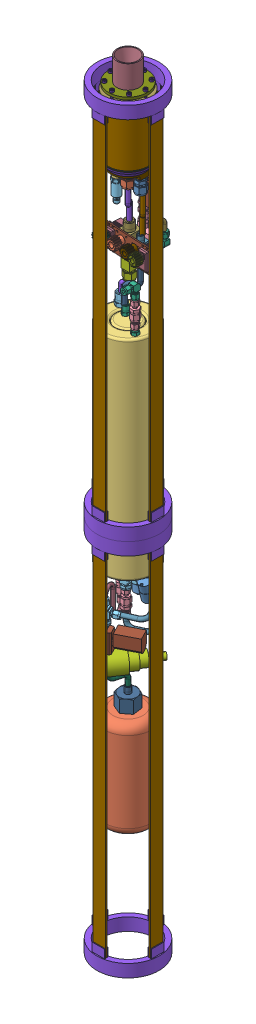
SolidWorks assembly Assemblage global, configuration Défaut. Lengths in mm.
Overall size (164.33 1851.66 164.33).
104 component instances, 54 part files, 42 mates.
Components (placement in the parent):
- AG2029-1: AG2029 [Défaut] at (-44.0948 -515.2209 332.3852) x (-0.187296 0.291343 -0.938104) z (-0.980646 0 0.195789) size (26.06 49.78 26.06)
- COPV-1: COPV [Défaut] at (-69.8493 -763.6515 345.7941) x (0.999999 0 -0.001097) z (0.001097 0 0.999999) size (111 247.05 111)
- reservoirs-1: reservoirs [Défaut] at (-63.3285 -459.1722 334.7401) x (0.861308 0 0.508083) z (0.508083 0 -0.861308) size (120 500 120)
- AG2029-2: AG2029 [Défaut] at (-74.1621 -512.8541 313.037) x (0.275712 0.022106 0.960986) z (0.961221 0 -0.275779) size (26.06 49.78 26.06)
- SS-CHS4-25-SwagelokCompany-3D-11-18-2022.stp-1: SS-CHS4-25-SwagelokCompany-3D-11-18-2022.stp [Défaut] at (-30.7659 29.6257 368.0986) x (0 1 0) z (-0.999992 0 0.003885) size (61.72 17.46 20.16)
- SS-CHS4-25-SwagelokCompany-3D-11-18-2022.stp-2: SS-CHS4-25-SwagelokCompany-3D-11-18-2022.stp [Défaut] at (-82.6779 -542.8366 338.0207) x (0 -1 0) z (0.566065 0 -0.82436) size (61.72 17.46 20.16)
- SS-CHS4-25-SwagelokCompany-3D-11-18-2022.stp-3: SS-CHS4-25-SwagelokCompany-3D-11-18-2022.stp [Défaut] at (-108.7134 -594.8623 323.1098) x (0 1 0) z (0.291825 0 -0.956472) size (61.72 17.46 20.16)
- SS-400-3-4TRT-SwagelokCompany-3D-11-18-2022.stp-2: SS-400-3-4TRT-SwagelokCompany-3D-11-18-2022.stp [Défaut] at (-88.4188 -547.9417 382.1181) x (0 -1 0) z (-0.911781 0 0.410677) size (61.21 20.32 39.95)
- SS-400-9-SwagelokCompany-3D-11-19-2022.stp-1: SS-400-9-SwagelokCompany-3D-11-19-2022.stp [Défaut] at (-32.0926 118.2717 394.9899) x (0.049277 0 -0.998785) z (0 1 0) size (35.14 14.22 35.14)
- SS-400-9-SwagelokCompany-3D-11-19-2022.stp-2: SS-400-9-SwagelokCompany-3D-11-19-2022.stp [Défaut] at (-85.1456 148.5076 291.806) x (-0.008726 -0.999962 0.000076) z (-0.008727 0 -0.999962) size (35.14 14.22 35.14)
- Détendeur Azote-1: Détendeur Azote [Défaut] at (-90.7987 -675.9247 398.6803) x (-0.827016 0 -0.562179) z (0.562179 0 -0.827016) size (50 50 118.8)
- structure_external-1: structure_external [Défaut] at (-54.807 -353.8101 198.1941) size (193.05 900.54 193.05)
  - ring-2: ring [Défaut] at (-15.0423 -34.6578 147.6) size (147.6 50 147.6)
  - rods_carbon-1: rods_carbon [Défaut] at (1414.5089 -1641.7579 78.8136) size (30 840 4)
  - rods_carbon-2: rods_carbon [Défaut] at (1414.5089 -1641.7579 212.3864) size (30 840 4)
  - rods_carbon-3: rods_carbon [Défaut] at (-83.8287 -1641.7579 -1281.9512) x (0 0 -1) z (1 0 0) size (30 840 4)
  - rods_carbon-4: rods_carbon [Défaut] at (53.7441 -1641.7579 1577.1512) x (0 0 1) z (-1 0 0) size (30 840 4)
  - ring-3: ring [Défaut] at (-15.0423 865.3422 147.6) x (-1 0 0) z (0 0 1) size (147.6 50 147.6)
  - case_rocket-1: case_rocket [Défaut] at (-15.0423 -35.1987 147.6) x (-0.316422 0 -0.948619) z (0.948619 0 -0.316422) size (152.6 900 152.6) (hidden)
- structure_external-2: structure_external [Défaut] at (-54.807 -1253.8101 198.1941) size (193.05 900.54 193.05)
  - ring-2: ring [Défaut] at (-15.0423 -34.6578 147.6) size (147.6 50 147.6)
  - rods_carbon-1: rods_carbon [Défaut] at (1414.5089 -1641.7579 78.8136) size (30 840 4)
  - rods_carbon-2: rods_carbon [Défaut] at (1414.5089 -1641.7579 212.3864) size (30 840 4)
  - rods_carbon-3: rods_carbon [Défaut] at (-83.8287 -1641.7579 -1281.9512) x (0 0 -1) z (1 0 0) size (30 840 4)
  - rods_carbon-4: rods_carbon [Défaut] at (53.7441 -1641.7579 1577.1512) x (0 0 1) z (-1 0 0) size (30 840 4)
  - ring-3: ring [Défaut] at (-15.0423 865.3422 147.6) x (-1 0 0) z (0 0 1) size (147.6 50 147.6)
  - case_rocket-1: case_rocket [Défaut] at (-15.0423 -35.1987 147.6) x (-0.316422 0 -0.948619) z (0.948619 0 -0.316422) size (152.6 900 152.6) (hidden)
- SS-16-RA-4-SwagelokCompany-3D-11-19-2022.stp-1: SS-16-RA-4-SwagelokCompany-3D-11-19-2022.stp [Défaut] at (-69.8493 -735.9786 345.7941) x (0 -1 0) z (0.129036 0 0.99164) size (49.78 41.27 47.66)
- SS-400-3-4TRT-SwagelokCompany-3D-11-18-2022.stp-6: SS-400-3-4TRT-SwagelokCompany-3D-11-18-2022.stp [Défaut] at (-82.6779 -492.923 338.0207) x (0 -1 0) z (-0.980646 0 0.195789) size (61.21 20.32 39.95)
- SS-400-3-4TRT-SwagelokCompany-3D-11-18-2022.stp-7: SS-400-3-4TRT-SwagelokCompany-3D-11-18-2022.stp [Défaut] at (-108.7134 -548.758 323.1098) x (0 1 0) z (-0.961221 0 0.275779) size (61.21 20.32 39.95)
- assemblage vanne-1: assemblage vanne [Défaut] at (-83.1452 273.6545 341.8828) x (0.998449 0 0.055666) z (0 -1 0) size (115.02 63.08 70.73)
  - support vanne servo-1: support vanne servo [Défaut] at (11.6117 -0.2898 118.0217) size (110 3 54)
  - SS-8P6T2-SwagelokCompany-3D-11-16-2022-1: SS-8P6T2-SwagelokCompany-3D-11-16-2022 [Défaut] at (-2.7383 -31.2778 99.9999) x (0 0 1) z (0 1 0) size (67.06 28.45 46.75)
  - Savox_SB2290SG Servo.stp-1: Savox_SB2290SG Servo.stp [Défaut] at (-30.1883 -2.5398 110) x (0 0 1) z (0 1 0) size (54 20.2 42.6)
  - SS-4P4T2-SwagelokCompany-3D-11-16-2022-1: SS-4P4T2-SwagelokCompany-3D-11-16-2022 [Défaut] at (30.8117 -21.3718 99.9999) x (0 0 1) z (0 1 0) size (48.26 18.8 31.12)
  - Savox_SB2290SG Servo.stp-3: Savox_SB2290SG Servo.stp [Défaut] at (55.6117 -2.5398 110.2) x (0 0 1) z (0 1 0) size (54 20.2 42.6)
  - GEAB1.5-20-15-B-10 v1.step-1: GEAB1.5-20-15-B-10 v1.step [Défaut] at (-30.1884 31.7992 99.9999) x (1 0 0) z (0 -1 0) size (33 33 15.01)
    - GEAB1.5-20-15-B-10_b.step-1: GEAB1.5-20-15-B-10_b.step [Défaut] at origin size (33 33 15.01)
  - GEAB1.5-15-15-B-10 v0.step-1: GEAB1.5-15-15-B-10 v0.step [Défaut] at (55.6116 16.3713 100.1999) x (1 0 0) z (0 1 0) size (25.44 25.39 15.01)
    - GEAB1.5-15-15-B-10_b.step-1: GEAB1.5-15-15-B-10_b.step [Défaut] at origin size (25.44 25.39 15.01)
  - GEAB1.5-15-15-B-10.stp-1: GEAB1.5-15-15-B-10.stp [Défaut] at (30.8117 27.2102 99.9999) x (0.94768 0 0.319221) z (0 -1 0) size (25.44 25.39 24.01)
    - SET-SCREW4-4.stp-1: SET-SCREW4-4.stp [Défaut] at (0 5 20) x (0 -1 0) z (-1 0 0) size (4 4 4)
    - GEAB1.5-15-15-B-10_b.stp-1: GEAB1.5-15-15-B-10_b.stp [Défaut] at origin size (25.44 25.39 24.01)
  - GEAB1.5-15-15-B-12.stp-1: GEAB1.5-15-15-B-12.stp [Défaut] at (-2.7383 27.2102 99.9999) x (0.774557 0 -0.632504) z (0 -1 0) size (25.44 25.39 24.01)
    - SET-SCREW4-3.stp-1: SET-SCREW4-3.stp [Défaut] at (0 6 20) x (0 -1 0) z (-1 0 0) size (3 4 4)
    - GEAB1.5-15-15-B-12_b.stp-1: GEAB1.5-15-15-B-12_b.stp [Défaut] at origin size (25.44 25.39 24.01)
  - raccord servo v2.step-1: raccord servo v2.step [Défaut] at (65.6117 16.7992 100.1999) x (1 0 0) z (0 -1 0) size (21 21 7)
  - raccord servo v2.step-2: raccord servo v2.step [Défaut] at (-20.1883 16.7992 99.9999) x (1 0 0) z (0 -1 0) size (21 21 7)
- SS-4R3A1-SwagelokCompany-3D-11-18-2022.stp-3: SS-4R3A1-SwagelokCompany-3D-11-18-2022.stp [Défaut] at (-84.9722 168.38 291.8045) x (0.99796 -0.008704 0.063248) z (0.008726 0.999962 -0.000076) size (51.64 20.24 98.81)
- SS-8-HN-RT-SwagelokCompany-3D-11-19-2022.stp-1: SS-8-HN-RT-SwagelokCompany-3D-11-19-2022.stp [Défaut] at (-108.7134 46.1814 323.1098) x (0 -1 0) z (0 0 1) size (46.74 22.23 25.66)
- SS-4-HN-RT-SwagelokCompany-3D-11-19-2022.stp-1: SS-4-HN-RT-SwagelokCompany-3D-11-19-2022.stp [Défaut] at (-82.8771 39.8314 338.3593) x (0 -1 0) z (0 0 1) size (35.56 14.29 16.5)
- SS-4-HN-RT-SwagelokCompany-3D-11-19-2022.stp-2: SS-4-HN-RT-SwagelokCompany-3D-11-19-2022.stp [Défaut] at (-82.6779 -467.2806 338.0207) x (0 -1 0) z (0 0 1) size (35.56 14.29 16.5)
- SS-4-HN-RT-SwagelokCompany-3D-11-19-2022.stp-3: SS-4-HN-RT-SwagelokCompany-3D-11-19-2022.stp [Défaut] at (-108.7134 -502.8406 323.1098) x (0 1 0) z (0 0 1) size (35.56 14.29 16.5)
- SS-4-HN-RT-SwagelokCompany-3D-11-19-2022.stp-5: SS-4-HN-RT-SwagelokCompany-3D-11-19-2022.stp [Défaut] at (-30.7659 39.8314 368.0986) x (0 -1 0) z (0 0 1) size (35.56 14.29 16.5)
- HC-810-3-SwagelokCompany-3D-11-19-2022.stp-1: HC-810-3-SwagelokCompany-3D-11-19-2022.stp [Défaut] at (-85.0713 157.6526 327.2391) x (0 -1 0) z (0.008727 0 0.999962) size (72.14 22.35 48.97)
- SS-400-9-SwagelokCompany-3D-11-19-2022.stp-5: SS-400-9-SwagelokCompany-3D-11-19-2022.stp [Défaut] at (-33.1986 194.8524 295.3224) x (-0.008131 -0.999924 -0.009303) z (0.99796 -0.008704 0.063248) size (35.14 14.22 35.14)
- tuyau_N20_bas_flex-1: tuyau_N20_bas_flex [Défaut] at (-67.8323 77.8106 330.25) x (0.985088 0 0.172054) z (-0.172054 0 0.985088) size (34 88 10)
- tuyau_N20_bas_flex-2: tuyau_N20_bas_flex [Défaut] at (-58.7499 259.7861 359.3238) x (0.634251 0 0.773127) z (-0.773127 0 0.634251) size (34 88 10)
- tuyau_eth_bas_flex-1: tuyau_eth_bas_flex [Défaut] at (-34.8493 240.253 345.7557) x (-0.688374 0 0.725356) z (-0.725356 0 -0.688374) size (10 102 32)
- tuyau_eth_haut_flex-1: tuyau_eth_haut_flex [Défaut] at (-18.4859 39.9352 328.5231) x (0.987138 0 -0.159869) z (0.159869 0 0.987138) size (43 115 10)
- soleno_quart-1: soleno_quart [Défaut] at (-61.5456 -650.9097 463.0875) x (0.457833 0 0.889038) z (0 1 0) size (28 80.02 47.02)
- soleno_quart-2: soleno_quart [Défaut] at (-20.3836 252.3792 237.2813) x (0.045071 0.008928 -0.998944) z (0.008131 0.999924 0.009303) size (28 80.02 47.02)
- tuyaux_vent_N20-1: tuyaux_vent_N20 [Défaut] at (-41.0336 189.9751 313.6956) x (-0.92086 0.011114 -0.389735) z (0.389808 0.005398 -0.92088) size (8 66 28)
- raccord1_pressure-1: raccord1_pressure [Défaut] at (-92.0789 -568.6899 372.0521) x (0.3218 0 0.946808) z (-0.946808 0 0.3218) size (70 88 8)
- raccord2_pressure-1: raccord2_pressure [Défaut] at (-56.8793 -576.2937 327.536) x (-0.410675 -0.003257 -0.911776) z (-0.001338 0.999995 -0.00297) size (46.01 60.01 60.01)
- raccord3_pressure-1: raccord3_pressure [Défaut] at (-73.9394 -725.8218 361.2221) x (0.256259 0 -0.966608) z (0.966608 0 0.256259) size (47.59 69.3 10)
- Demo A2 98mm V02-1: Demo A2 98mm V02 [Standard] at (-69.8493 355.3689 345.7941) x (0.998956 0 -0.04569) z (-0.04569 0 -0.998956) size (138.59 315.92 138.59)
  - Injector 98mm V02-1: Injector 98mm V02 [Standard] at (0 -14 0) size (138.59 129.3 138.59)
    - Faceplate 98mm-1: Faceplate 98mm [Standard] x (-0.707107 0 -0.707107) z (0.707107 0 -0.707107) size (98 14 98)
    - Manifold 98mm-1: Manifold 98mm [Standard] at (0 14 0) size (98 15 98)
    - Core 98mm-1: Core 98mm [Standard] at (0 -3 0) size (80 44 80)
    - SS-810-1-4RS-SwagelokCompany-3D-10-18-2022.stp-1: SS-810-1-4RS-SwagelokCompany-3D-10-18-2022.stp [Standard] at (29 75.766 0) x (0 -1 0) z (-0.5 0 0.866025) size (44.7 22.35 25.81)
    - SS-810-1-8RS-SwagelokCompany-3D-10-18-2022.stp-1: SS-810-1-8RS-SwagelokCompany-3D-10-18-2022.stp [Standard] at (0 76.528 0) x (0 -1 0) z (0.5 0 0.866025) size (47.5 26.99 31.16)
    - Pressure sensor tube-1: Pressure sensor tube [Standard] at (-26 -2 0) x (0 0 -1) z (1 0 0) size (18 70 18)
    - Diverter 98mm-1: Diverter 98mm [Standard] at (0 -7.2 0) x (0.998923 0 0.046395) z (-0.046395 0 0.998923) size (19 24.43 19)
    - CAD_STP_500_0186-1: CAD_STP_500_0186 [Standard] at (-26 48.3 0) x (0 1 0) z (-0.050182 0 0.99874) size (73.8 19.02 21)
      - CAD_STP_500_0186.stp-1: CAD_STP_500_0186.stp [Standard] at origin size (73.8 19.02 21)
        - _PL54XX_P1.stp-1: _PL54XX_P1.stp [Standard] at origin size (73.8 19.02 21)
    - CB6-25.stp-1: CB6-25.stp [Standard] at (-20.5061 34 20.5061) x (0 -1 0) z (0 0 1) size (31 10 10)
    - CB6-25.stp-2: CB6-25.stp [Standard] at (-20.5061 34 -20.5061) x (0 -1 0) z (-1 0 0) size (31 10 10)
    - CB6-25.stp-3: CB6-25.stp [Standard] at (20.5061 34 -20.5061) x (0 -1 0) z (0 0 -1) size (31 10 10)
    - CB6-25.stp-4: CB6-25.stp [Standard] at (20.5061 34 20.5061) x (0 -1 0) z (1 0 0) size (31 10 10)
    - M6 bolt seal-1: M6 bolt seal [Standard] at (-20.5061 34 20.5061) x (0.989025 0 -0.147746) z (0 -1 0) size (10 10 1)
    - M6 bolt seal-2: M6 bolt seal [Standard] at (-20.5061 34 -20.5061) x (0.147746 0 0.989025) z (0 -1 0) size (10 10 1)
    - M6 bolt seal-3: M6 bolt seal [Standard] at (20.5061 34 -20.5061) x (-0.989025 0 0.147746) z (0 -1 0) size (10 10 1)
    - M6 bolt seal-4: M6 bolt seal [Standard] at (20.5061 34 20.5061) x (-0.147746 0 -0.989025) z (0 -1 0) size (10 10 1)
    - Seal pressure sensor-1: Seal pressure sensor [Standard] at (-26 41 0) size (14.4 1 14.4)
  - Chamber 98mm-1: Chamber 98mm [Standard] at (0 -69.5 0) x (-0.996776 0 0.080231) z (-0.080231 0 -0.996776) size (98 133 98)
  - Thermal Insulation-1: Thermal Insulation [Standard] at (0 -12 0) x (0 0 1) z (0 -1 0) size (91.69 91.69 112)
  - Thermal Insulation faceplate-1: Thermal Insulation faceplate [Standard] at (0 -14 0) x (-1 0 0) z (0 -1 0) size (91.7 91.7 2)
  - Nozzle converging 98mm -1: Nozzle converging 98mm  [Standard] at (0 -120 0) x (0 -1 0) z (0 0 1) size (22 98.3 99.09)
  - Nozzle diverging 98mm -1: Nozzle diverging 98mm  [Standard] at (0 -142.2 0) x (0 -1 0) z (-0.490695 0 0.871332) size (71.92 64 64)
  - Seal chamber-1: Seal chamber [Standard] at (0 -2 0) x (0 -1 0) z (0 0 1) size (1 98 98)
  - Seal chamber-2: Seal chamber [Standard] at (0 -136 0) x (0 -1 0) z (0 0 1) size (1 98 98)
  - Seal nozzle-1: Seal nozzle [Standard] at (0 -142.2 0) x (0.805443 0 -0.592674) z (0 1 0) size (56 56 1)
  - Nozzle Insert holder-1: Nozzle Insert holder [Standard] at (0 -147.2 0) x (-0.707107 0 -0.707107) z (-0.707107 0 0.707107) size (92 6 92)
  - CB5-20.stp-1: CB5-20.stp [Standard] at (-40 -153.2 0) x (0 1 0) z (0 0 1) size (25 8.5 8.5)
  - CB5-20.stp-2: CB5-20.stp [Standard] at (-28.2843 -153.2 28.2843) x (0 1 0) z (0.707107 0 0.707107) size (25 8.5 8.5)
  - CB5-20.stp-3: CB5-20.stp [Standard] at (0 -153.2 40) x (0 1 0) z (1 0 0) size (25 8.5 8.5)
  - CB5-20.stp-4: CB5-20.stp [Standard] at (28.2843 -153.2 28.2843) x (0 1 0) z (0.707107 0 -0.707107) size (25 8.5 8.5)
  - CB5-20.stp-5: CB5-20.stp [Standard] at (40 -153.2 0) x (0 1 0) z (0 0 -1) size (25 8.5 8.5)
  - CB5-20.stp-6: CB5-20.stp [Standard] at (28.2843 -153.2 -28.2843) x (0 1 0) z (-0.707107 0 -0.707107) size (25 8.5 8.5)
  - CB5-20.stp-7: CB5-20.stp [Standard] at (0 -153.2 -40) x (0 1 0) z (-1 0 0) size (25 8.5 8.5)
  - CB5-20.stp-8: CB5-20.stp [Standard] at (-28.2843 -153.2 -28.2843) x (0 1 0) z (-0.707107 0 0.707107) size (25 8.5 8.5)
Mates (geometry in assembly coordinates):
- Coaxiale1: concentric aligned: cylinder of structure_external-1/ring-3 through (-69.8493 481.5321 345.7941) axis (0 1 0) radius 62; cylinder of structure_external-2/ring-3 through (-69.8493 -418.4679 345.7941) axis (0 1 0) radius 62
- Coïncidente1: coincident anti-aligned: plane of structure_external-1/ring-2 through (-69.8493 -388.4679 345.7941) normal (0 -1 0); plane of structure_external-2/ring-3 through (-69.8493 -388.4679 345.7941) normal (0 1 0)
- Coaxiale2: concentric aligned: cylinder of reservoirs-1 through (-69.8493 13.4954 345.7941) axis (0 1 0) radius 60; cylinder of structure_external-1/ring-3 through (-69.8493 481.5321 345.7941) axis (0 1 0) radius 62
- Coaxiale5: concentric aligned: cylinder of COPV-1 through (-69.8493 -740.9319 345.7941) axis (0 1 0) radius 55.5; cylinder of reservoirs-1 through (-69.8493 13.4954 345.7941) axis (0 1 0) radius 60
- Distance2: distance = 300 mm anti-aligned: plane of reservoirs-1 through (-54.6068 -481.5046 319.9549) normal (0 -1 0); plane of COPV-1 through (-69.8493 -781.5046 345.7941) normal (0 1 0)
- Coaxiale8: concentric anti-aligned: cylinder of COPV-1 through (-69.8493 -740.9319 345.7941) axis (0 1 0) radius 55.5; cylinder of SS-16-RA-4-SwagelokCompany-3D-11-19-2022.stp-1 through (-69.8493 -748.6329 345.7941) axis (0 -1 0) radius 6.858
- Coïncidente4: coincident anti-aligned: plane of COPV-1 through (-69.8493 -766.4577 345.7941) normal (0 1 0); plane of SS-16-RA-4-SwagelokCompany-3D-11-19-2022.stp-1 through (-69.8493 -766.4577 345.7941) normal (0 -1 0)
- Coaxiale14: concentric anti-aligned: cylinder of reservoirs-1 through (-108.7134 18.4954 323.1098) axis (0 1 0) radius 6.7462; cone of SS-8-HN-RT-SwagelokCompany-3D-11-19-2022.stp-1 through (-108.7134 6.2234 323.1098) axis (0 -1 0)
- Coaxiale15: concentric anti-aligned: cylinder of reservoirs-1 through (-82.8771 18.4954 338.3593) axis (0 1 0) radius 5.5626; cone of SS-4-HN-RT-SwagelokCompany-3D-11-19-2022.stp-1 through (-82.8771 9.3743 338.3593) axis (0 -1 0)
- Coïncidente8: coincident anti-aligned: plane of reservoirs-1 through (-54.6068 18.4954 319.9549) normal (0 1 0); plane of SS-4-HN-RT-SwagelokCompany-3D-11-19-2022.stp-1 through (-82.8771 18.4954 338.3593) normal (0 -1 0)
- Coïncidente9: coincident anti-aligned: plane of reservoirs-1 through (-39.3643 18.4954 294.1156) normal (0 1 0); plane of SS-8-HN-RT-SwagelokCompany-3D-11-19-2022.stp-1 through (-108.7134 18.4954 323.1098) normal (0 -1 0)
- Coaxiale16: concentric anti-aligned: cylinder of reservoirs-1 through (-82.6779 -481.5046 338.0207) axis (0 -1 0) radius 5.5626; cone of SS-4-HN-RT-SwagelokCompany-3D-11-19-2022.stp-2 through (-82.6779 -472.3834 338.0207) axis (0 1 0)
- Coaxiale17: concentric anti-aligned: cylinder of reservoirs-1 through (-108.7134 -481.5046 323.1098) axis (0 -1 0) radius 3.3782; cone of SS-4-HN-RT-SwagelokCompany-3D-11-19-2022.stp-3 through (-108.7134 -472.3834 323.1098) axis (0 1 0)
- Coïncidente10: coincident anti-aligned: plane of reservoirs-1 through (-54.6068 -481.5046 319.9549) normal (0 -1 0); plane of SS-4-HN-RT-SwagelokCompany-3D-11-19-2022.stp-2 through (-82.6779 -481.5046 338.0207) normal (0 1 0)
- Coïncidente11: coincident anti-aligned: plane of reservoirs-1 through (-39.3643 -481.5046 294.1156) normal (0 -1 0); plane of SS-4-HN-RT-SwagelokCompany-3D-11-19-2022.stp-3 through (-108.7134 -481.5046 323.1098) normal (0 1 0)
- Coaxiale20: concentric anti-aligned: cylinder of reservoirs-1 through (-30.7659 18.4954 368.0986) axis (0 1 0) radius 3.3782; cone of SS-4-HN-RT-SwagelokCompany-3D-11-19-2022.stp-5 through (-30.7659 9.3743 368.0986) axis (0 -1 0)
- Coïncidente14: coincident anti-aligned: plane of reservoirs-1 through (-39.3643 18.4954 294.1156) normal (0 1 0); plane of SS-4-HN-RT-SwagelokCompany-3D-11-19-2022.stp-5 through (-30.7659 18.4954 368.0986) normal (0 -1 0)
- Coïncidente15: coincident anti-aligned: plane of SS-CHS4-25-SwagelokCompany-3D-11-18-2022.stp-1 through (-27.2099 91.3477 368.0848) normal (0 1 0); plane of SS-400-9-SwagelokCompany-3D-11-19-2022.stp-1 through (-30.9411 91.3477 371.6503) normal (0 -1 0)
- Coaxiale23: concentric aligned: cylinder of SS-CHS4-25-SwagelokCompany-3D-11-18-2022.stp-1 through (-30.7659 46.1357 368.0986) axis (0 1 0) radius 4.4768; cone of SS-4-HN-RT-SwagelokCompany-3D-11-19-2022.stp-5 through (-30.7659 34.7286 368.0986) axis (0 1 0)
- Coïncidente16: coincident aligned: plane of SS-CHS4-25-SwagelokCompany-3D-11-18-2022.stp-1 through (-34.3219 29.6257 368.1124) normal (0 -1 0); circle of SS-4-HN-RT-SwagelokCompany-3D-11-19-2022.stp-5
- Coaxiale25: concentric anti-aligned: cylinder of SS-CHS4-25-SwagelokCompany-3D-11-18-2022.stp-1 through (-30.7659 83.4737 368.0986) axis (0 -1 0) radius 7.112; cylinder of SS-400-9-SwagelokCompany-3D-11-19-2022.stp-1 through (-30.7659 99.2217 368.0986) axis (0 1 0) radius 7.112
- Coaxiale26: concentric aligned: cone of assemblage vanne-1/SS-8P6T2-SwagelokCompany-3D-11-16-2022-1 through (-85.0713 146.9046 327.2391) axis (0 -1 0); cylinder of HC-810-3-SwagelokCompany-3D-11-19-2022.stp-1 through (-85.0713 147.3656 327.2391) axis (0 -1 0) radius 11.176
- Coïncidente17: coincident aligned: plane of assemblage vanne-1/SS-8P6T2-SwagelokCompany-3D-11-16-2022-1 through (-84.7861 140.1266 322.124) normal (0 -1 0); plane of HC-810-3-SwagelokCompany-3D-11-19-2022.stp-1 through (-84.981 140.1266 337.5892) normal (0 -1 0)
- Coaxiale27: concentric anti-aligned: cylinder of SS-400-9-SwagelokCompany-3D-11-19-2022.stp-2 through (-85.2143 121.5846 310.8573) axis (-0.008727 0 -0.999962) radius 7.112; cylinder of HC-810-3-SwagelokCompany-3D-11-19-2022.stp-1 through (-85.2963 121.5846 301.459) axis (0.008727 0 0.999962) radius 11.176
- Coaxiale29: concentric aligned: cylinder of SS-400-9-SwagelokCompany-3D-11-19-2022.stp-2 through (-85.2143 140.6339 291.8066) axis (-0.008726 -0.999962 0.000076) radius 7.112; cone of SS-4R3A1-SwagelokCompany-3D-11-18-2022.stp-3 through (-85.1914 143.2579 291.8064) axis (-0.008726 -0.999962 0.000076)
- Coaxiale31: concentric anti-aligned: cylinder of SS-4R3A1-SwagelokCompany-3D-11-18-2022.stp-3 through (-52.273 168.0949 293.8769) axis (-0.99796 0.008704 -0.063248) radius 7.112; cylinder of SS-400-9-SwagelokCompany-3D-11-19-2022.stp-5 through (-52.4287 168.0962 293.867) axis (0.99796 -0.008704 0.063248) radius 7.112
- Coaxiale32: concentric aligned: cone of SS-8-HN-RT-SwagelokCompany-3D-11-19-2022.stp-1 through (-108.7134 39.4035 323.1098) axis (0 1 0); cylinder of tuyau_N20_bas_flex-1 through (-108.7134 24.0606 323.1098) axis (0 1 0) radius 5
- Coaxiale33: concentric aligned: cylinder of HC-810-3-SwagelokCompany-3D-11-19-2022.stp-1 through (-85.0713 95.8036 327.2391) axis (0 1 0) radius 11.176; cylinder of tuyau_N20_bas_flex-1 through (-85.0713 78.0606 327.2391) axis (0 1 0) radius 5
- Coaxiale35: concentric aligned: cone of assemblage vanne-1/SS-8P6T2-SwagelokCompany-3D-11-16-2022-1 through (-85.0713 200.4046 327.2391) axis (0 1 0); cylinder of tuyau_N20_bas_flex-2 through (-85.0713 206.0361 327.2391) axis (0 1 0) radius 5
- Coaxiale38: concentric anti-aligned: cylinder of assemblage vanne-1/SS-4P4T2-SwagelokCompany-3D-11-16-2022-1 through (-51.842 157.076 333.9252) axis (0 -1 0) radius 3.556; cylinder of tuyau_eth_haut_flex-1 through (-51.842 101.3283 333.9252) axis (0 1 0) radius 5
- Coaxiale42: concentric anti-aligned: cylinder of SS-400-9-SwagelokCompany-3D-11-19-2022.stp-5 through (-33.2626 186.979 295.2491) axis (-0.008131 -0.999924 -0.009303) radius 7.112; cylinder of tuyaux_vent_N20-1 through (-33.2753 185.4247 295.2347) axis (0.008131 0.999924 0.009303) radius 4
- Coaxiale43: concentric anti-aligned: cylinder of soleno_quart-2 through (-40.5306 251.8267 314.2711) axis (-0.008131 -0.999924 -0.009303) radius 3.3782; cylinder of tuyaux_vent_N20-1 through (-40.7299 227.3136 314.043) axis (0.008131 0.999924 0.009303) radius 4
- Coaxiale52: concentric anti-aligned: cylinder of SS-400-3-4TRT-SwagelokCompany-3D-11-18-2022.stp-6 through (-82.6779 -506.3532 338.0207) axis (0 -1 0) radius 5.5563; cylinder of SS-4-HN-RT-SwagelokCompany-3D-11-19-2022.stp-2 through (-82.6779 -490.6257 338.0207) axis (0 1 0) radius 6.7056
- Coaxiale53: concentric aligned: cylinder of SS-400-3-4TRT-SwagelokCompany-3D-11-18-2022.stp-7 through (-108.7134 -491.0658 323.1098) axis (0 -1 0) radius 6.5785; cone of SS-4-HN-RT-SwagelokCompany-3D-11-19-2022.stp-3 through (-108.7134 -497.7377 323.1098) axis (0 -1 0)
- Coaxiale54: concentric anti-aligned: cylinder of SS-CHS4-25-SwagelokCompany-3D-11-18-2022.stp-2 through (-82.6779 -550.7106 338.0207) axis (0 -1 0) radius 7.112; cylinder of SS-400-3-4TRT-SwagelokCompany-3D-11-18-2022.stp-6 through (-82.6779 -550.6152 338.0207) axis (0 1 0) radius 6.5785
- Coaxiale55: concentric anti-aligned: cylinder of SS-CHS4-25-SwagelokCompany-3D-11-18-2022.stp-3 through (-108.7134 -541.0143 323.1098) axis (0 -1 0) radius 7.112; cylinder of SS-400-3-4TRT-SwagelokCompany-3D-11-18-2022.stp-7 through (-108.7134 -540.884 323.1098) axis (0 1 0) radius 7.112
- Coaxiale57: concentric anti-aligned: cylinder of Détendeur Azote-1 through (-82.3661 -703.4247 386.2751) axis (0 1 0) radius 6.35; cylinder of soleno_quart-1 through (-82.3661 -650.9097 386.2751) axis (0 -1 0) radius 3.3782
- Coaxiale58: concentric anti-aligned: cylinder of SS-CHS4-25-SwagelokCompany-3D-11-18-2022.stp-3 through (-108.7134 -586.9883 323.1098) axis (0 1 0) radius 7.112; cylinder of raccord1_pressure-1 through (-108.7134 -582.5813 323.1098) axis (0 -1 0) radius 4
- Coaxiale61: concentric anti-aligned: cone of AG2029-2 through (-86.1686 -519.802 316.6415) axis (0.961221 0 -0.275779); cylinder of SS-400-3-4TRT-SwagelokCompany-3D-11-18-2022.stp-7 through (-88.2048 -519.802 317.2257) axis (-0.961221 0 0.275779) radius 3.175
- Coaxiale63: concentric anti-aligned: cone of AG2029-1 through (-56.7843 -521.879 332.8509) axis (0.980646 0 -0.195789); cylinder of SS-400-3-4TRT-SwagelokCompany-3D-11-18-2022.stp-6 through (-61.7548 -521.879 333.8433) axis (-0.980646 0 0.195789) radius 3.175
- Coaxiale66: concentric aligned: cone of SS-16-RA-4-SwagelokCompany-3D-11-19-2022.stp-1 through (-69.8493 -741.0815 345.7941) axis (0 1 0); cylinder of raccord3_pressure-1 through (-69.8493 -761.0282 345.7941) axis (0 1 0) radius 5
- Coaxiale67: concentric aligned: cylinder of structure_external-1/ring-3 through (-69.8493 481.5321 345.7941) axis (0 1 0) radius 62; cylinder of Demo A2 98mm V02-1/Chamber 98mm-1 through (-69.8493 424.8689 345.7941) axis (0 1 0) radius 49
